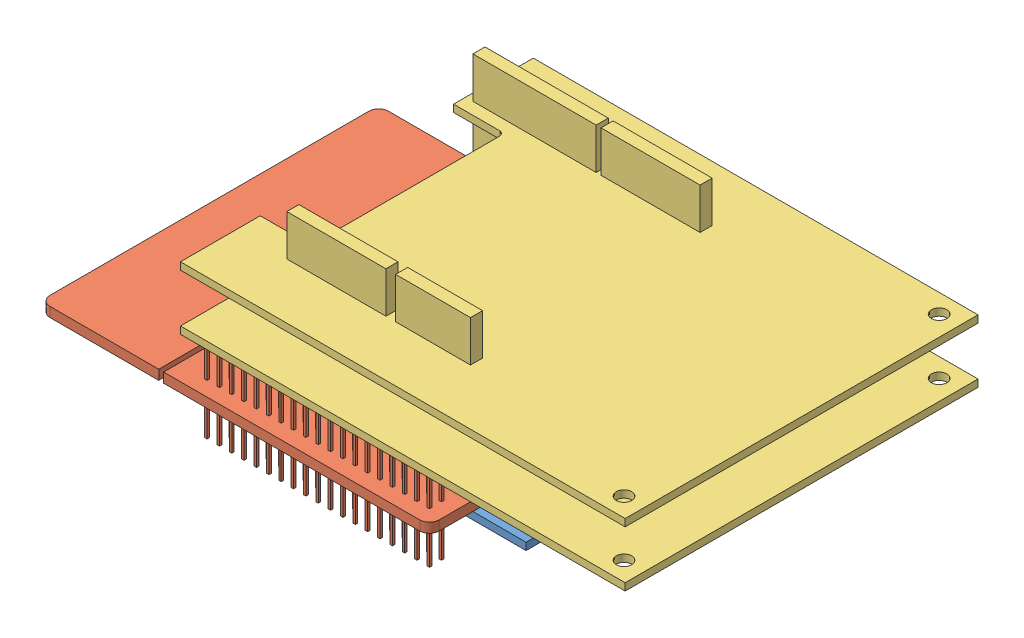
SolidWorks assembly 1.2.5 elektronika, configuration Domyślna. Lengths in mm.
Overall size (129 45 75.5).
4 component instances, 3 part files, 10 mates.
Components (placement in the parent):
- 1.2.5.1 plytka podstawa-1: 1.2.5.1 plytka podstawa [Domyślna] at origin size (88 10 55)
- 1.2.5.2 nucleo-f411re-1: 1.2.5.2 nucleo-f411re [Domyślna] at (1.6807 11.5 7.1981) x (-1 0 0) z (0 0 -1) size (82.5 19 70)
- 1.2.5.3 x-nucleo-ihm02a1-1: 1.2.5.3 x-nucleo-ihm02a1 [Domyślna] at (39 23.5 11.5) size (92 18.5 73)
- 1.2.5.3 x-nucleo-ihm02a1-2: 1.2.5.3 x-nucleo-ihm02a1 [Domyślna] at (39 35 11.5) size (92 18.5 73)
Mates (geometry in assembly coordinates):
- Odległość1: distance = 10 mm anti-aligned: plane of 1.2.5.2 nucleo-f411re-1 through (1.6807 13.5 7.1981) normal (0 1 0); plane of 1.2.5.3 x-nucleo-ihm02a1-1 through (2.5 23.5 30.5) normal (0 -1 0)
- Wspólnie2: coincident aligned: plane of 1.2.5.2 nucleo-f411re-1 through (41.5 22 -15.1842) normal (0 0 -1); plane of 1.2.5.3 x-nucleo-ihm02a1-1 through (41.5 33.5 -15.1842) normal (0 0 -1)
- Wspólnie3: coincident aligned: plane of 1.2.5.2 nucleo-f411re-1 through (-5.5 22 -15.1842) normal (-1 0 0); plane of 1.2.5.3 x-nucleo-ihm02a1-1 through (-5.5 33.5 -15.1842) normal (-1 0 0)
- Odległość2: distance = 10 mm anti-aligned: plane of 1.2.5.3 x-nucleo-ihm02a1-1 through (2.5 25 30.5) normal (0 1 0); plane of 1.2.5.3 x-nucleo-ihm02a1-2 through (2.5 35 30.5) normal (0 -1 0)
- Wspólnie4: coincident aligned: plane of 1.2.5.2 nucleo-f411re-1 through (41.5 22 -15.1842) normal (0 0 -1); plane of 1.2.5.3 x-nucleo-ihm02a1-2 through (41.5 45 -15.1842) normal (0 0 -1)
- Wspólnie5: coincident aligned: plane of 1.2.5.2 nucleo-f411re-1 through (-5.5 22 -15.1842) normal (-1 0 0); plane of 1.2.5.3 x-nucleo-ihm02a1-2 through (-5.5 45 -15.1842) normal (-1 0 0)
- Wspólnie6: coordinate: point of 1.2.5.1 plytka podstawa-1; point of assembly
- Odległość3: distance = 10 mm anti-aligned: plane of 1.2.5.1 plytka podstawa-1 through (0 1.5 0) normal (0 1 0); plane of 1.2.5.2 nucleo-f411re-1 through (1.6807 11.5 7.1981) normal (0 -1 0)
- Szerokość1: width anti-aligned: plane of 1.2.5.1 plytka podstawa-1 through (41 10 -16.5) normal (1 0 0); plane of 1.2.5.1 plytka podstawa-1 through (-7.5 10 -16.5) normal (-1 0 0); plane of 1.2.5.2 nucleo-f411re-1 through (-6.5 22.7071 -20.5) normal (-1 0 0); plane of 1.2.5.2 nucleo-f411re-1 through (40 22.7071 -20.5) normal (1 0 0)
- Szerokość2: width aligned: plane of 1.2.5.1 plytka podstawa-1 through (-7.5 10 -21.5) normal (0 0 -1); plane of 1.2.5.1 plytka podstawa-1 through (-7.5 10 -16.5) normal (0 0 1); plane of 1.2.5.2 nucleo-f411re-1 through (39.5 22.7071 -20.5) normal (0 0 -1); plane of 1.2.5.2 nucleo-f411re-1 through (39.5 22.7071 -17.5) normal (0 0 1)
